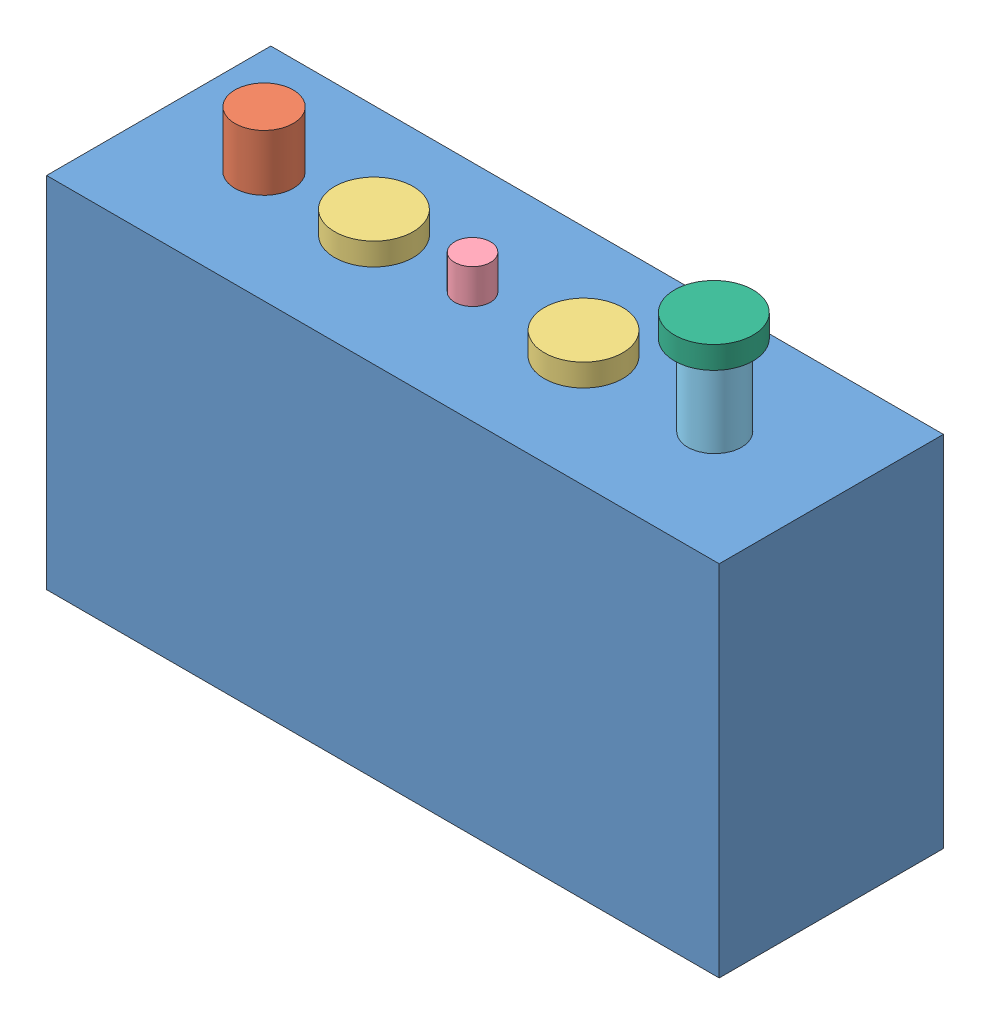
SolidWorks assembly switchbox, configuration Default. Lengths in mm.
Overall size (167.21 120.21 50).
11 component instances, 8 part files, 13 mates.
Components (placement in the parent):
- switchbox-1: switchbox [Default] at (-78.9745 42.3812 28.118) size (150 80 50)
- fuse-1: fuse [Default] at (-55.4745 54.9109 3.118) x (0.995817 0 0.091369) z (-0.091369 0 0.995817) size (13 41 13)
- estart-1: estart [Default] at (-30.9745 42.3812 3.118) x (-0.641577 0 -0.767059) z (0.767059 0 -0.641577) size (17.5 25 17.5)
- d-light-1: d-light [Default] at (-8.9745 50.0815 3.118) x (0.865774 0 -0.500435) z (0.500435 0 0.865774) size (8 41.5 8)
- estart-2: estart [Default] at (15.7755 42.3812 3.118) x (0.975409 0 0.220404) z (-0.220404 0 0.975409) size (17.5 25 17.5)
- estopcomplete-1: estopcomplete [Default] at (27.5214 30.3812 13.1108) x (1 0 0.000411) z (-0.000411 0 1) size (35 57.5 24.22)
  - Estop-1: Estop [Default] at origin size (35 52.5 20)
  - estop-top-1: estop-top [Default] at (17.364 35 -9.9351) x (-0.837169 0 -0.546944) z (-0.546944 0 0.837169) size (17.5 5 17.5)
- AS size 8-1: AS size 8 [Default] at (-78.9745 -17.6188 3.118) x (0 1 0) z (0 0 1) size (19.5 33.5 32)
- AS size 8-2: AS size 8 [Default] at (-41.4745 -37.6188 3.118) x (0.999711 0 0.024026) z (0.024026 0 -0.999711) size (19.5 33.5 32)
- AS size 10_JDB-4: AS size 10_JDB [Default] at (33.5255 -37.6188 3.118) x (0.997965 0 -0.06376) z (-0.06376 0 -0.997965) size (19.5 33.5 32)
Mates (geometry in assembly coordinates):
- Lock5: lock: unknown of switchbox-1; unknown of fuse-1
- Concentric3: concentric aligned: circle of switchbox-1; circle of estart-1
- Coincident11: coincident aligned: plane of switchbox-1 through (-78.9745 42.3812 28.118) normal (0 1 0); circle of estart-1
- Lock6: lock: unknown of switchbox-1; unknown of d-light-1
- Coincident13: coincident aligned: plane of switchbox-1 through (-78.9745 42.3812 28.118) normal (0 1 0); circle of estart-2
- Coincident14: coincident aligned: circle of switchbox-1; cylinder of estart-2 through (15.7755 22.3812 3.118) axis (0 1 0) radius 6.75
- Distance1: distance = 12 mm aligned: plane of estopcomplete-1/Estop-1 through (27.5214 30.3812 13.1108) normal (0 1 0); plane of switchbox-1 through (-78.9745 42.3812 28.118) normal (0 1 0)
- Coincident15: coincident anti-aligned: plane of switchbox-1 through (-78.9745 -37.6188 -21.882) normal (-1 0 0); plane of AS size 8-1 through (-78.9745 -17.6188 3.118) normal (1 0 0)
- Concentric4: concentric anti-aligned: circle of switchbox-1; cylinder of AS size 8-1 through (-62.6845 -17.6188 3.118) axis (-1 0 0) radius 6
- Concentric6: concentric anti-aligned: circle of switchbox-1; cylinder of AS size 8-2 through (-41.4745 -21.3288 3.118) axis (0 -1 0) radius 6
- Coincident17: coincident anti-aligned: plane of switchbox-1 through (-78.9745 -37.6188 28.118) normal (0 -1 0); plane of AS size 8-2 through (-41.4745 -37.6188 3.118) normal (0 1 0)
- Concentric7: concentric anti-aligned: circle of switchbox-1; cylinder of AS size 10_JDB-4 through (33.5255 -21.3288 3.118) axis (0 -1 0) radius 7.5
- Coincident18: coincident anti-aligned: plane of switchbox-1 through (-78.9745 -37.6188 28.118) normal (0 -1 0); plane of AS size 10_JDB-4 through (33.5255 -37.6188 3.118) normal (0 1 0)
